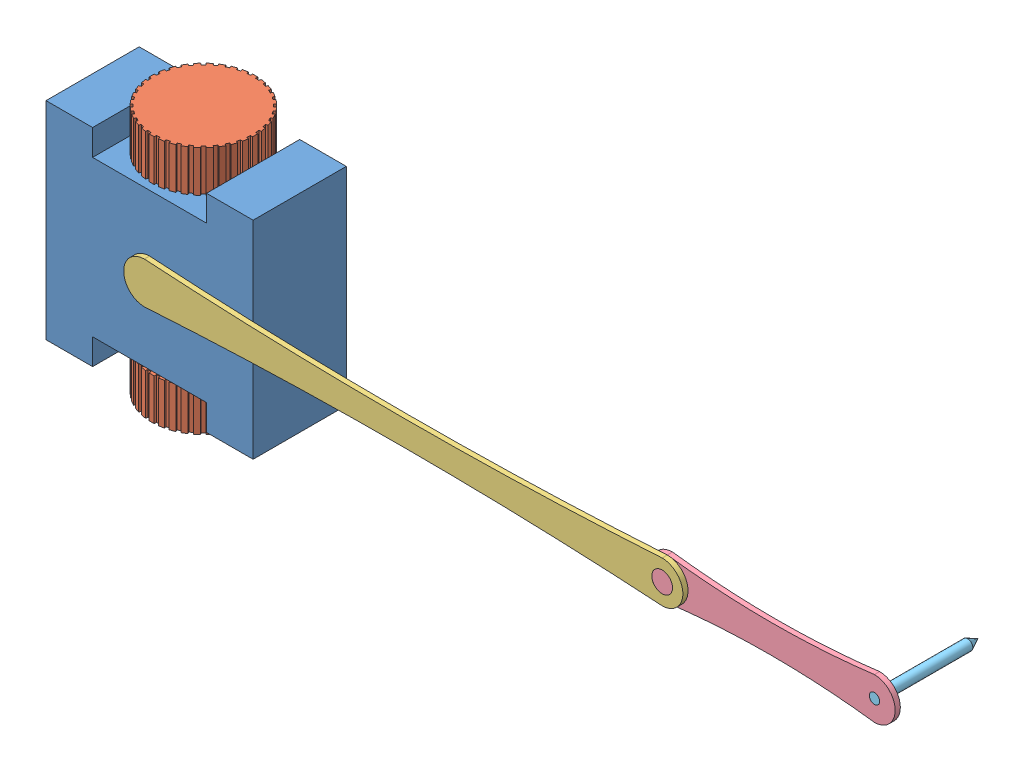
SolidWorks assembly Mobile Manipulator Robot, configuration Default. Lengths in mm.
Overall size (4100 1200 535).
8 component instances, 6 part files, 21 mates.
Components (placement in the parent):
- Mobile Base-1: Mobile Base [Default] at origin size (1000 1000 450)
- Wheel-1: Wheel [Default] at (0 -400 190) x (0 -1 0) z (0 0 1) size (200 500 500)
- Wheel-2: Wheel [Default] at (0 400 190) x (0 1 0) z (0 0 1) size (200 500 500)
- Proximal Link-1: Proximal Link [Default] at (1250 0 450) size (2700 200 50)
- Distal Link-1: Distal Link [Default] at (3000 0 450) x (1 0 0) z (0 0 -1) size (1200 200 50)
- Pen-1: Pen [Default] at (3500 0 450) x (-0.706537 0.707676 0) z (0 0 -1) size (50 50 500)
- Support-1: Support [Default] at (350 0 25) x (-1 0 0) z (0 0 -1) size (100 100 85)
- Support-2: Support [Default] at (-350 0 25) x (-1 0 0) z (0 0 -1) size (100 100 85)
Mates (geometry in assembly coordinates):
- Coincident1: coincident anti-aligned: plane of Mobile Base-1 through (0 -500 190) normal (0 -1 0); plane of Wheel-1 through (0 -500 190) normal (0 1 0)
- Concentric1: concentric aligned: cylinder of Mobile Base-1 through (0 -500 190) axis (0 1 0) radius 50; cylinder of Wheel-1 through (0 -500 190) axis (0 1 0) radius 50
- Coincident2: coincident anti-aligned: plane of Mobile Base-1 through (0 500 190) normal (0 1 0); plane of Wheel-2 through (0 500 190) normal (0 -1 0)
- Concentric2: concentric aligned: cylinder of Mobile Base-1 through (0 500 190) axis (0 -1 0) radius 50; cylinder of Wheel-2 through (0 500 190) axis (0 -1 0) radius 50
- Coincident3: coincident anti-aligned: plane of Mobile Base-1 through (0 0 425) normal (0 0 1); plane of Proximal Link-1 through (0 0 425) normal (0 0 -1)
- Concentric3: concentric aligned: cylinder of Mobile Base-1 through (0 0 425) axis (0 0 1) radius 50; cylinder of Proximal Link-1 through (0 0 425) axis (0 0 1) radius 50
- Coincident4: coincident aligned: plane of Proximal Link-1 through (1875 10030.4496 475) normal (0 0 1); plane of Distal Link-1 through (2500 0 475) normal (0 0 1)
- Concentric4: concentric anti-aligned: cylinder of Proximal Link-1 through (2500 0 450) axis (0 0 1) radius 50; cylinder of Distal Link-1 through (2500 0 475) axis (0 0 -1) radius 50
- Coincident5: coincident aligned: plane of Distal Link-1 through (3250 -2034.3135 450) normal (0 0 1); plane of Pen-1 through (3500 0 450) normal (0 0 1)
- Concentric5: concentric anti-aligned: cylinder of Distal Link-1 through (3500 0 450) axis (0 0 -1) radius 25; cylinder of Pen-1 through (3500 0 0) axis (0 0 1) radius 25
- Coincident6: coincident anti-aligned: plane of Mobile Base-1 through (400 -50 25) normal (-1 0 0); plane of Support-1 through (400 -50 -10) normal (1 0 0)
- Coincident7: coincident anti-aligned: plane of Mobile Base-1 through (300 -50 25) normal (0 1 0); plane of Support-1 through (400 -50 -10) normal (0 -1 0)
- Coincident8: coincident anti-aligned: plane of Mobile Base-1 through (0 0 25) normal (0 0 -1); plane of Support-1 through (350 0 25) normal (0 0 1)
- Coincident9: coincident anti-aligned: plane of Mobile Base-1 through (-400 -50 25) normal (1 0 0); plane of Support-2 through (-400 -50 -10) normal (-1 0 0)
- Coincident10: coincident anti-aligned: plane of Mobile Base-1 through (-300 -50 25) normal (0 1 0); plane of Support-2 through (-300 -50 -10) normal (0 -1 0)
- Coincident11: coincident anti-aligned: plane of Mobile Base-1 through (0 0 25) normal (0 0 -1); plane of Support-2 through (-350 0 25) normal (0 0 1)
- Parallel1: parallel aligned: plane of Wheel-1 through (383.8236 244.2859 793.2495) normal (0 0 1)
- Parallel2: parallel aligned: plane of Wheel-2 through (383.8236 1044.2859 793.2495) normal (0 0 1)
- Parallel3: parallel aligned: plane of Proximal Link-1 through (1633.8236 644.2859 1053.2495) normal (0 1 0)
- Parallel4: parallel anti-aligned: plane of Distal Link-1 through (3383.8236 644.2859 1053.2495) normal (0 -1 0)
- Coincident16: coordinate: unknown of Mobile Base-1
